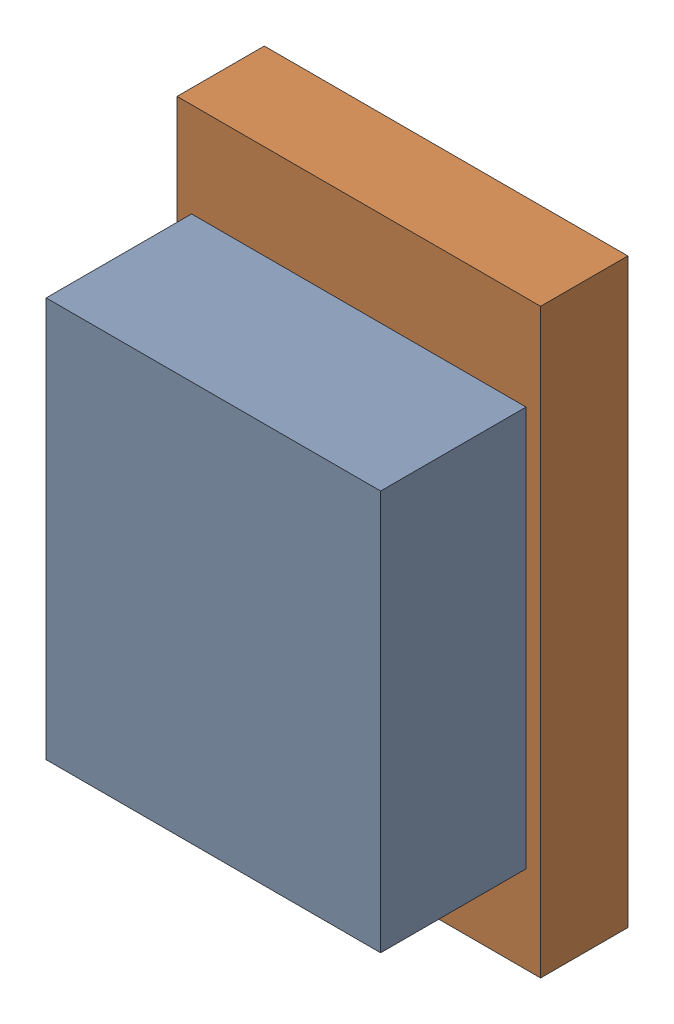
SolidWorks assembly LED2_Motor_4Kanaloa_v2.0.0_Loko, configuration Default. Lengths in mm.
Overall size (1.25 2 0.8).
4 component instances, 2 part files, 0 mates.
Components (placement in the parent):
- 334788912-1: 334788912 [Default] at (55.5752 79.2355 0) size (1.15 1.38 0.8)
  - Extruded_31-1: Extruded_31 [Default] at origin size (1.15 1.38 0.8)
- 425429200-1: 425429200 [Default] at (55.5752 79.248 0) size (1.25 2 0.3)
  - Extruded_32-1: Extruded_32 [Default] at origin size (1.25 2 0.3)
